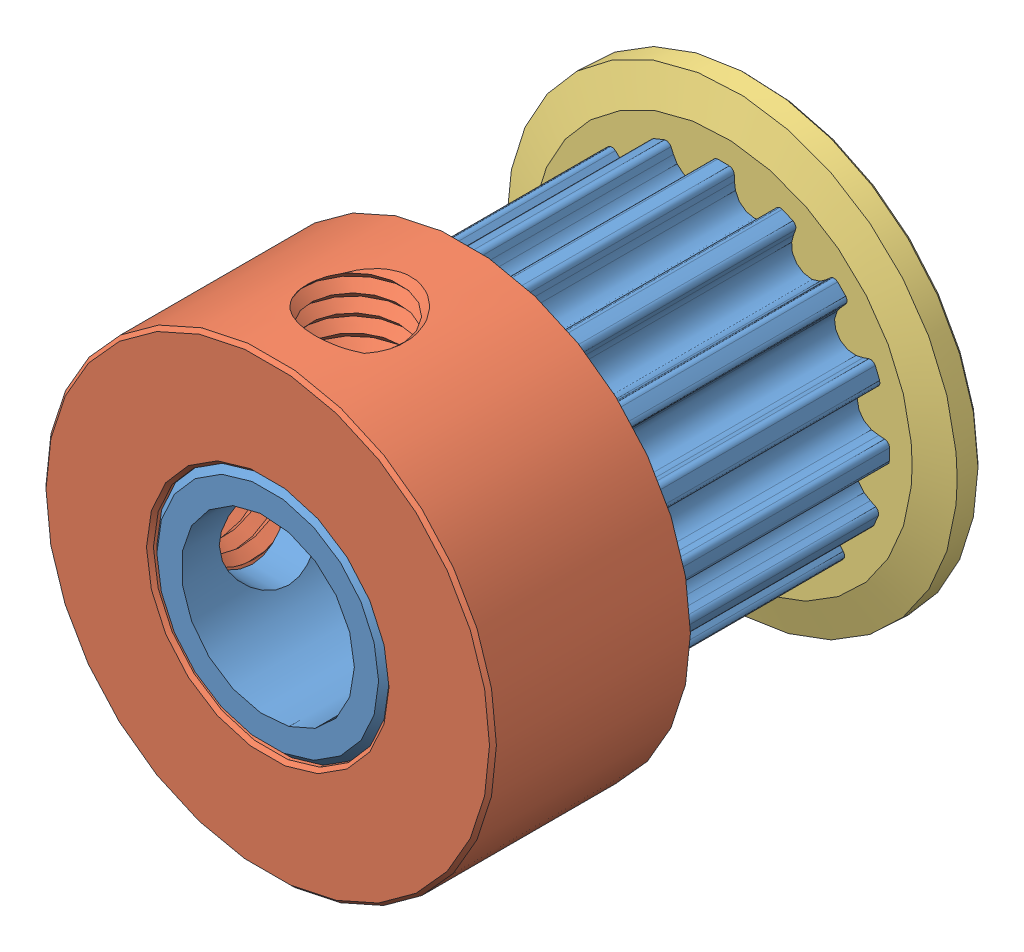
SolidWorks assembly 16 teeth pulley GT2 6mm ASSEMBLY, configuration По умолчанию. Lengths in mm.
Overall size (13.18 13.18 14.1).
3 component instances, 3 part files, 4 mates.
Components (placement in the parent):
- Pulley 16th GT2-1: Pulley 16th GT2 [По умолчанию] at (-0.2522 -0.3848 7.05) size (9.7 9.7 14.1)
- Cheeck thick-1: Cheeck thick [По умолчанию] at (-0.2522 -0.3848 21.15) x (-1 0.000287 0) z (0 0 -1) size (13.17 13.17 6)
- Cheeck thin-1: Cheeck thin [По умолчанию] at (-0.2522 -0.3848 7.05) size (13 13 1)
Mates (geometry in assembly coordinates):
- Coincident1: coincident anti-aligned: plane of Pulley 16th GT2-1 through (-0.2522 -0.3848 15.15) normal (0 0 1); plane of Cheeck thick-1 through (-0.2522 -0.3848 15.15) normal (0 0 -1)
- Concentric1: concentric anti-aligned: cylinder of Pulley 16th GT2-1 through (-0.2522 -0.3848 21.15) axis (0 0 -1) radius 3.4; cylinder of Cheeck thick-1 through (-0.2522 -0.3848 15.15) axis (0 0 1) radius 3.4
- Coincident2: coincident anti-aligned: plane of Pulley 16th GT2-1 through (-0.2522 -0.3848 8.05) normal (0 0 -1); plane of Cheeck thin-1 through (-0.2522 -0.3848 8.05) normal (0 0 1)
- Concentric2: concentric aligned: cylinder of Pulley 16th GT2-1 through (-0.2522 -0.3848 8.05) axis (0 0 -1) radius 3.4; cylinder of Cheeck thin-1 through (-0.2522 -0.3848 8.05) axis (0 0 -1) radius 3.4
